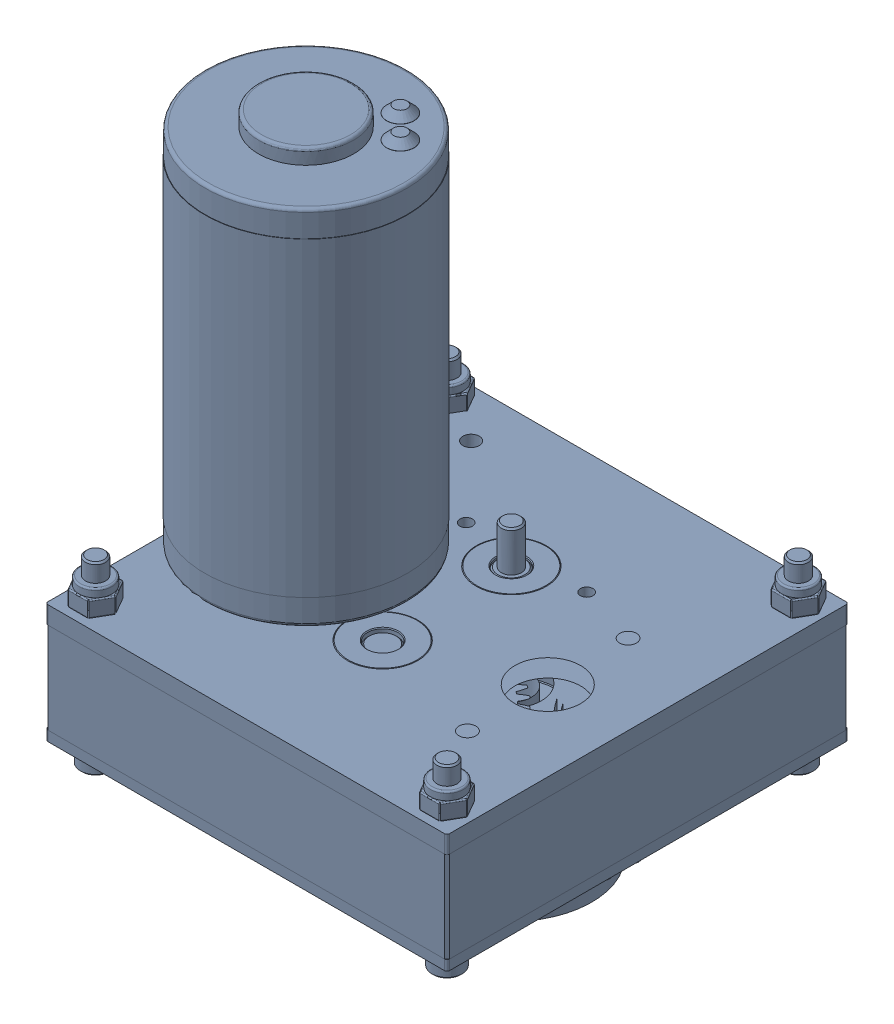
SolidWorks assembly Assem3^harris_chassis, configuration Default. Lengths in mm.
Overall size (133.71 204.92 127).
2 component instances, 2 part files, 2 mates.
Components (placement in the parent):
- tb_with_cim-1: tb_with_cim [Default] at origin size (133.71 204.92 127)
- sprocket_spacer_22t hub-1: sprocket_spacer_22t hub [Default] at (13.6731 -64.5366 -35.1556) x (0 -1 0) z (0 0 1) size (17.37 71.91 71.96)
Mates (geometry in assembly coordinates):
- Concentric45: concentric anti-aligned: cylinder of tb_with_cim-1 through (13.6731 -79.883 -35.1556) axis (0 -1 0) radius 6.3373; circle of sprocket_spacer_22t hub-1
- Coincident59: coincident anti-aligned: circle of tb_with_cim-1; plane of sprocket_spacer_22t hub-1 through (13.6731 -79.375 -35.1556) normal (0 -1 0)
